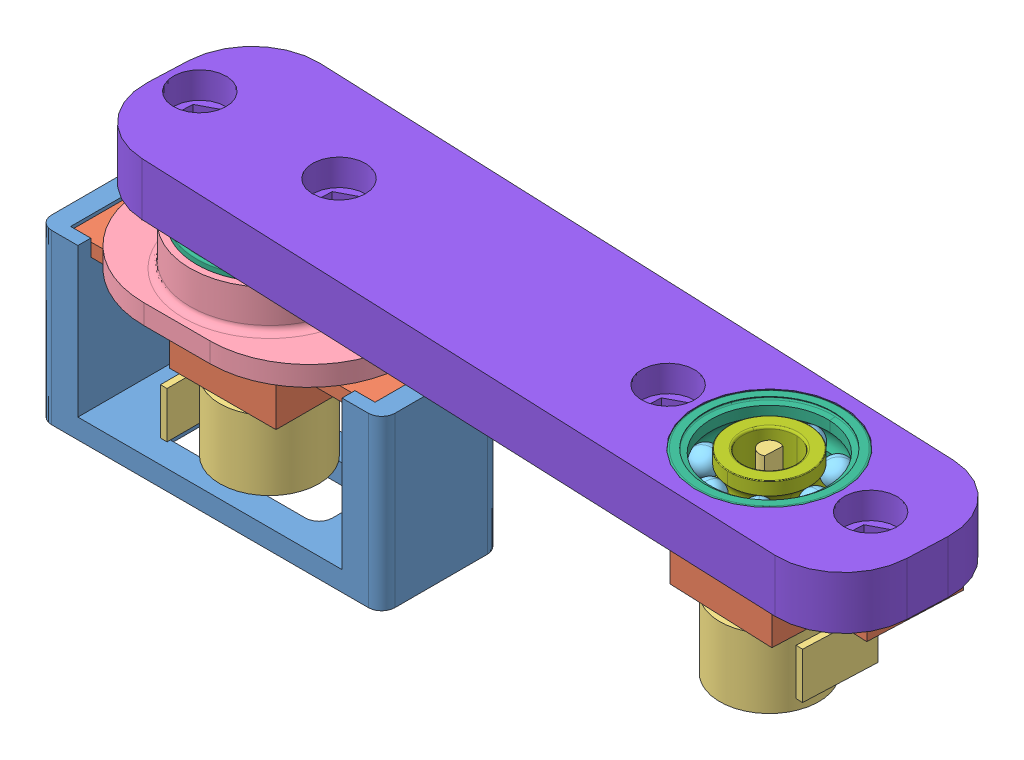
SolidWorks assembly assy_gic_kinematic_2d_robot_arm_MK1_v1, configuration Default. Lengths in mm.
Overall size (130.44 45.5 32.47).
29 component instances, 9 part files, 13 mates.
Components (placement in the parent):
- 2D_robotArm_base_lower_v1-1: 2D_robotArm_base_lower_v1 [Default] at origin size (52 25.5 18)
- DfRobot_stepper_FIT0503_mount_v3-1: DfRobot_stepper_FIT0503_mount_v3 [Default] at (0 25 0) x (1 0 0) z (0 0 -1) size (46.1 10.6 14.1)
- Df_Robot_stepper_FIT0503-1: Df_Robot_stepper_FIT0503 [Default] at (0 23 0) x (1 0 0) z (0 0 -1) size (16 31 15.5)
- base_bearing_holder_v1-1: base_bearing_holder_v1 [Default] at (0 25 0) size (39.93 9 28)
- 608_Z-1: 608_Z [Default] at (0 35 0) x (0 -1 0) z (0.546944 0 -0.837169) size (7 22 22)
  - 608_Z_11-1: 608_Z_11 [Default] x (1 0 0) z (0 -0.781831 0.62349) size (3.97 3.97 3.97)
  - 608_Z_11-2: 608_Z_11 [Default] x (1 0 0) z (0 -0.974928 -0.222521) size (3.97 3.97 3.97)
  - 608_Z_11-3: 608_Z_11 [Default] x (1 0 0) z (0 -0.433884 -0.900969) size (3.97 3.97 3.97)
  - 608_Z_11-4: 608_Z_11 [Default] x (1 0 0) z (0 0.433884 -0.900969) size (3.97 3.97 3.97)
  - 608_Z_11-5: 608_Z_11 [Default] x (1 0 0) z (0 0.974928 -0.222521) size (3.97 3.97 3.97)
  - 608_Z_11-6: 608_Z_11 [Default] x (1 0 0) z (0 0.781831 0.62349) size (3.97 3.97 3.97)
  - 608_Z_11-7: 608_Z_11 [Default] at origin size (3.97 3.97 3.97)
  - 608_Z_19-1: 608_Z_19 [Default] at origin size (7 22 22)
  - 608_Z_21-1: 608_Z_21 [Default] at origin size (7 19.2 19.2)
- sub_assy_robot_arm_link1-1: sub_assy_robot_arm_link1 [Default] at (43.9632 37.5 1.7997) x (0.999163 0 0.040902) z (-0.040902 0 0.999163) size (120 31 26)
  - 2D_robotArm_link1_v1-1: 2D_robotArm_link1_v1 [Default] at origin size (120 8 26)
  - robot_arm_link_bearing_insert_mk1-1: robot_arm_link_bearing_insert_mk1 [Default] at (-44 0 0) x (1 0 0) z (0 0 -1) size (30 9 11.5)
  - DfRobot_stepper_FIT0503_mount_v3-1: DfRobot_stepper_FIT0503_mount_v3 [Default] at (35 0 0) x (1 0 0) z (0 0 -1) size (46.1 10.6 14.1)
  - Df_Robot_stepper_FIT0503-1: Df_Robot_stepper_FIT0503 [Default] at (35 -2 0) x (-1 0 0) z (0 0 1) size (16 31 15.5)
  - 608_Z-1: 608_Z [Default] at (35 8 0) x (0 -1 0) z (0 0 1) size (7 22 22)
    - 608_Z_11-1: 608_Z_11 [Default] x (1 0 0) z (0 -0.781831 0.62349) size (3.97 3.97 3.97)
    - 608_Z_11-2: 608_Z_11 [Default] x (1 0 0) z (0 -0.974928 -0.222521) size (3.97 3.97 3.97)
    - 608_Z_11-3: 608_Z_11 [Default] x (1 0 0) z (0 -0.433884 -0.900969) size (3.97 3.97 3.97)
    - 608_Z_11-4: 608_Z_11 [Default] x (1 0 0) z (0 0.433884 -0.900969) size (3.97 3.97 3.97)
    - 608_Z_11-5: 608_Z_11 [Default] x (1 0 0) z (0 0.974928 -0.222521) size (3.97 3.97 3.97)
    - 608_Z_11-6: 608_Z_11 [Default] x (1 0 0) z (0 0.781831 0.62349) size (3.97 3.97 3.97)
    - 608_Z_11-7: 608_Z_11 [Default] at origin size (3.97 3.97 3.97)
    - 608_Z_19-1: 608_Z_19 [Default] at origin size (7 22 22)
    - 608_Z_21-1: 608_Z_21 [Default] at origin size (7 19.2 19.2)
Mates (geometry in assembly coordinates):
- Coincident1: coincident anti-aligned: plane of 2D_robotArm_base_lower_v1-1 through (23.05 23 -7.05) normal (-1 0 0); plane of DfRobot_stepper_FIT0503_mount_v3-1 through (23.05 23 7.05) normal (1 0 0)
- Coincident2: coincident anti-aligned: plane of 2D_robotArm_base_lower_v1-1 through (0 23 0) normal (0 1 0); plane of DfRobot_stepper_FIT0503_mount_v3-1 through (0 23 0) normal (0 -1 0)
- Coincident3: coincident anti-aligned: plane of 2D_robotArm_base_lower_v1-1 through (0 0 0) normal (0 0 1); plane of DfRobot_stepper_FIT0503_mount_v3-1 through (0 25 0) normal (0 0 -1)
- Coincident4: coincident aligned: line of DfRobot_stepper_FIT0503_mount_v3-1 through (1 -4.5 23) axis (0 0 1); line of Df_Robot_stepper_FIT0503-1 through (2 -4.5 21) axis (0 0 1)
- Coincident6: coincident aligned: line of DfRobot_stepper_FIT0503_mount_v3-1 through (1 4.5 23) axis (0 0 1); line of Df_Robot_stepper_FIT0503-1 through (2 4.5 21) axis (0 0 1)
- Coincident7: coincident anti-aligned: plane of DfRobot_stepper_FIT0503_mount_v3-1 through (0 23 0) normal (0 -1 0); plane of Df_Robot_stepper_FIT0503-1 through (0 23 0) normal (0 1 0)
- Coincident8: coincident aligned: line of DfRobot_stepper_FIT0503_mount_v3-1 through (2 -16 23) axis (0 0 1); line of base_bearing_holder_v1-1 through (1 -16 25) axis (0 0 1)
- Coincident9: coincident aligned: line of DfRobot_stepper_FIT0503_mount_v3-1 through (2 16 23) axis (0 0 1); line of base_bearing_holder_v1-1 through (1 16 25) axis (0 0 1)
- Coincident10: coincident anti-aligned: plane of DfRobot_stepper_FIT0503_mount_v3-1 through (0 25 0) normal (0 1 0); plane of base_bearing_holder_v1-1 through (0 25 0) normal (0 -1 0)
- Coincident11: coincident aligned: line of base_bearing_holder_v1-1 through (5 0 34) axis (0 0 -1); line of 608_Z-1/608_Z_21-1 through (10.5173 0 31.9558) axis (0 0 -1)
- Coincident12: coincident anti-aligned: plane of base_bearing_holder_v1-1 through (0 28 0) normal (0 1 0); plane of 608_Z-1/608_Z_19-1 through (-8.0368 28 -5.2507) normal (0 -1 0)
- Coincident13: coincident aligned: line of 608_Z-1/608_Z_21-1 through (12.8802 0 24.0666) axis (0 0 1); line of sub_assy_robot_arm_link1-1/robot_arm_link_bearing_insert_mk1-1 through (6.5 0 28.5) axis (0 0 1)
- Coincident14: coincident anti-aligned: plane of 608_Z-1/608_Z_21-1 through (-5.0021 35 -3.268) normal (0 1 0); circle of sub_assy_robot_arm_link1-1/robot_arm_link_bearing_insert_mk1-1
